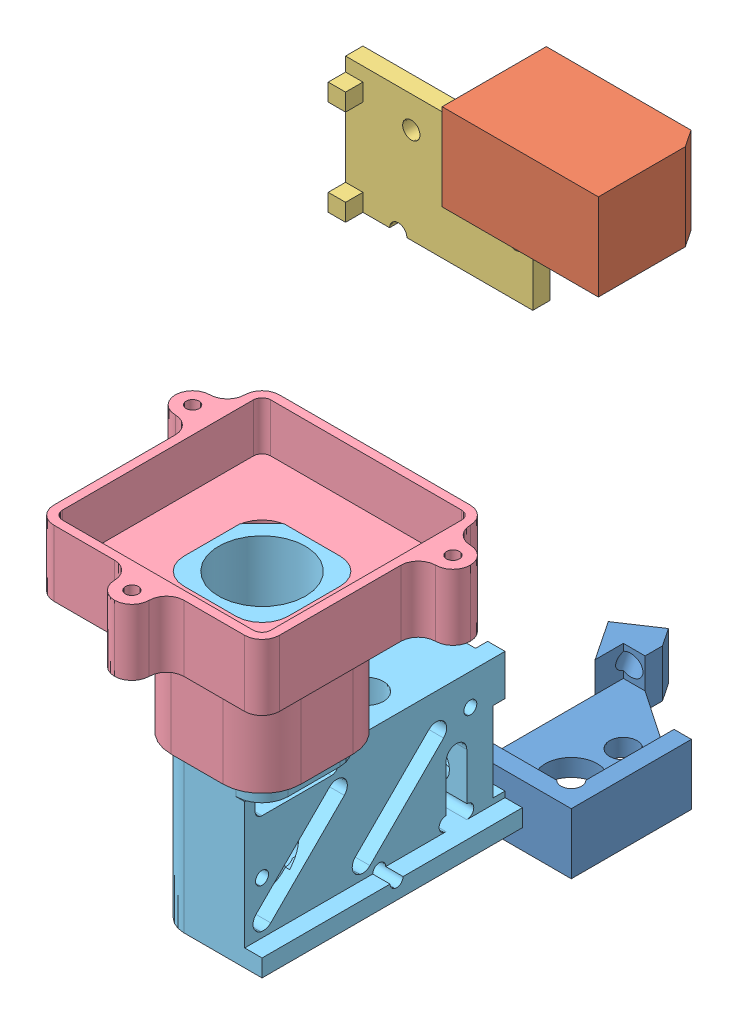
SolidWorks assembly Assembled_Miniscope, configuration Default. Lengths in mm.
Overall size (43.36 25.72 51.44).
5 component instances, 5 part files, 2 mates.
Components (placement in the parent):
- MS_Baseplatev3-1: MS_Baseplatev3 [Default] at (5.6193 5.5143 9.8294) size (9.02 3.5 12.54)
- MS_CAPv3-1: MS_CAPv3 [Default] at (-13.5332 14.8611 -7.8824) size (9 5 6)
- MS_FilterCoverv3-1: MS_FilterCoverv3 [Default] at (-20.0386 12.8295 -8.6094) size (10.79 7.3 2)
- MS_FocusSliderv3.2-1: MS_FocusSliderv3.2 [Default] at (8.5313 20.436 32.0594) x (0 0 -1) z (1 0 0) size (15 10.8 17)
- MS_MainBodyv3.2-1: MS_MainBodyv3.2 [Default] at (8.5313 11.136 27.5594) x (0 0 -1) z (1 0 0) size (15 17.3 6)
Mates (geometry in assembly coordinates):
- Parallel1: parallel aligned: plane of MS_FocusSliderv3.2-1 through (3.8974 500020.436 29.1933) normal (-0.707107 0 -0.707107); plane of MS_MainBodyv3.2-1 through (5.5313 28.436 30.3094) normal (-0.707107 0 -0.707107)
- Coincident3: coincident aligned: circle of MS_FocusSliderv3.2-1; circle of MS_MainBodyv3.2-1
